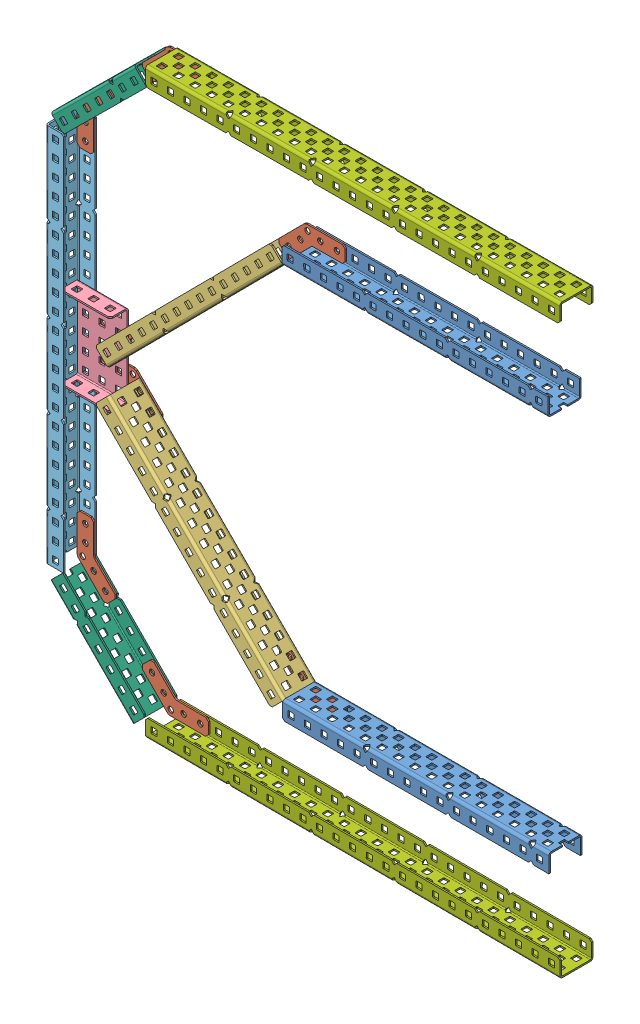
SolidWorks assembly Assem1, configuration Default. Lengths in mm.
Overall size (407.34 448.6 26.57).
18 component instances, 7 part files, 55 mates.
Components (placement in the parent):
- Channel 121-25 Aluminum-1: Channel 121-25 Aluminum [Default] at (-71.4802 130.2056 305.0856) size (203.98 13.87 25.4)
- 45 Degree Gusset Steel-1: 45 Degree Gusset Steel [Default] at (-111.3904 134.6957 291.8218) x (0.707107 0.707107 0) z (-0.707107 0.707107 0) size (29.13 1.17 50.81)
- Channel 121-15 Steel-1: Channel 121-15 Steel [Default] at (-213.9281 246.2136 305.0856) x (0.707107 -0.707107 0) z (0 0 1) size (190.5 13.87 25.4)
- 45 Degree Gusset Steel-4: 45 Degree Gusset Steel [Default] at (-228.1337 251.439 289.485) x (-0.707107 -0.707107 0) z (0.707107 -0.707107 0) size (29.13 1.17 50.81)
- Channel 151-15 Steel-1: Channel 151-15 Steel [Default] at (-405.6135 259.1091 290.6534) x (1 0 0) z (0 1 0) size (37.98 13.87 63.5)
- Channel 121-25 Aluminum-5: Channel 121-25 Aluminum [Default] at (-71.9919 420.4651 299.2845) x (0.999992 0.004 0) z (0 0 -1) size (203.98 13.87 25.4)
- 45 Degree Gusset Steel-11: 45 Degree Gusset Steel [Default] at (-111.8839 415.8408 290.6534) x (0.70993 -0.704273 0) z (-0.704273 -0.70993 0) size (29.13 1.17 50.81)
- Channel 121-15 Steel-5: Channel 121-15 Steel [Default] at (-213.9927 303.9315 299.2845) x (0.704273 0.70993 0) z (0 0 -1) size (190.5 13.87 25.4)
- 45 Degree Gusset Steel-12: 45 Degree Gusset Steel [Default] at (-228.1774 298.6493 288.3166) x (-0.70993 0.704273 0) z (0.704273 0.70993 0) size (29.13 1.17 50.81)
- 45 Degree Gusset Steel-13: 45 Degree Gusset Steel [Default] at (-262.514 115.5096 289.485) x (0.707107 0.707107 0) z (0.707107 -0.707107 0) size (29.13 1.17 50.81)
- 45 Degree Gusset Steel-14: 45 Degree Gusset Steel [Default] at (-262.514 434.5504 290.6534) x (0.707107 -0.707107 0) z (0.707107 0.707107 0) size (29.13 1.17 50.81)
- Channel 121-23 Aluminum-1: Channel 121-23 Aluminum [Default] at (-279.6787 130.0198 303.9172) x (0 1 0) z (0 0 1) size (291.03 13.87 25.4)
- Channel 121-7 Aluminum-1: Channel 121-7 Aluminum [Default] at (-257.2319 448.735 303.9172) x (0.70993 0.704273 0) z (0 0 1) size (89.86 13.87 25.4)
- Channel 121-7 Aluminum-4: Channel 121-7 Aluminum [Default] at (-231.9773 75.7112 303.9172) x (-0.704273 0.70993 0) z (0 0 1) size (89.86 13.87 25.4)
- 45 Degree Gusset Steel-15: 45 Degree Gusset Steel [Default] at (-191.6839 59.4664 289.485) x (0.004 0.999992 0) z (0.999992 -0.004 0) size (29.13 1.17 50.81)
- Channel 121-25 Al-1: Channel 121-25 Al [Default] at (86.8646 52.0022 303.9172) x (-0.999992 0.004 0) z (0 0 1) size (317.5 13.87 25.4)
- Channel 121-25 Al-3: Channel 121-25 Al [Default] at (86.8646 498.0578 298.1161) x (-0.999992 -0.004 0) z (0 0 -1) size (317.5 13.87 25.4)
- 45 Degree Gusset Steel-17: 45 Degree Gusset Steel [Default] at (-191.6839 490.5935 290.6534) x (0.004 -0.999992 0) z (0.999992 0.004 0) size (29.13 1.17 50.81)
Mates (geometry in assembly coordinates):
- Coincident2: coincident: plane of Channel 121-25 Aluminum-1 through (-97.9454 130.2056 314.885) normal (0 -1 0); plane of 45 Degree Gusset Steel-1 through (-72.52 130.2056 290.6534) normal (0 1 0)
- Coincident3: coincident: plane of Channel 121-25 Aluminum-1 through (-97.9454 130.2056 290.6534) normal (0 0 1); plane of 45 Degree Gusset Steel-1 through (-124.8608 139.1858 290.6534) normal (0 0 -1)
- Distance1: distance = 2.286 mm: cylinder of 45 Degree Gusset Steel-1 through (-78.87 123.8556 290.6534) axis (0 0 1) radius 2.0701; plane of Channel 121-25 Aluminum-1 through (-76.584 126.167 289.485) normal (-1 0 0)
- Coincident7: coincident: plane of 45 Degree Gusset Steel-1 through (-97.92 130.2056 290.6534) normal (0.707107 0.707107 0); plane of Channel 121-15 Steel-1 through (-232.6418 264.9274 314.885) normal (-0.707107 -0.707107 0)
- Coincident8: coincident: plane of 45 Degree Gusset Steel-1 through (-124.8608 139.1858 290.6534) normal (0 0 -1); plane of Channel 121-15 Steel-1 through (-232.6418 264.9274 290.6534) normal (0 0 1)
- Distance2: distance = 2.286 mm: plane of Channel 121-15 Steel-1 through (-103.6494 130.2235 289.485) normal (-0.707107 0.707107 0); cylinder of 45 Degree Gusset Steel-1 through (-106.9003 130.2056 290.6534) axis (0 0 1) radius 2.0701
- Coincident9: coincident: plane of Channel 121-15 Steel-1 through (-232.6418 264.9274 314.885) normal (-0.707107 -0.707107 0); plane of 45 Degree Gusset Steel-4 through (-232.6239 264.9094 288.3166) normal (0.707107 0.707107 0)
- Distance3: distance = 2.286 mm: cylinder of 45 Degree Gusset Steel-4 through (-223.6436 246.9489 288.3166) axis (0 0 1) radius 2.0701; plane of Channel 121-15 Steel-1 through (-220.3928 246.9669 289.485) normal (-0.707107 0.707107 0)
- Coincident11: coincident: plane of Channel 121-15 Steel-1 through (-232.6418 264.9274 289.485) normal (0 0 -1); plane of 45 Degree Gusset Steel-4 through (-214.6634 246.9489 289.485) normal (0 0 1)
- Coincident12: coincident: plane of 45 Degree Gusset Steel-4 through (-214.6634 246.9489 289.485) normal (0 0 1); plane of Channel 151-15 Steel-1 through (-432.0787 307.0086 289.485) normal (0 0 -1)
- Distance4: distance = 2.286 mm: plane of Channel 151-15 Steel-1 through (-250.2401 259.9932 292.025) normal (0 1 0); cylinder of 45 Degree Gusset Steel-4 through (-260.6541 262.2792 288.3166) axis (0 0 1) radius 2.0701
- Distance17: distance = 2.286 mm: cylinder of 45 Degree Gusset Steel-12 through (-260.6541 287.6792 289.485) axis (0 0 -1) radius 2.0701; plane of Channel 151-15 Steel-1 through (-250.2401 285.3932 292.025) normal (0 1 0)
- Coincident34: coincident: plane of Channel 151-15 Steel-1 through (-432.0787 307.0086 289.485) normal (0 0 -1); plane of 45 Degree Gusset Steel-12 through (-214.725 303.1933 289.485) normal (0 0 1)
- Coincident36: coincident: plane of Channel 121-15 Steel-5 through (-232.6315 285.143 289.485) normal (-0.70993 0.704273 0); plane of 45 Degree Gusset Steel-12 through (-232.6136 285.1611 289.485) normal (0.70993 -0.704273 0)
- Distance21: distance = 2.286 mm: plane of Channel 121-15 Steel-5 through (-220.4543 303.1524 314.885) normal (-0.704273 -0.70993 0); cylinder of 45 Degree Gusset Steel-12 through (-223.7052 303.1573 289.485) axis (0 0 -1) radius 2.0701
- Coincident37: coincident: plane of Channel 121-15 Steel-5 through (-232.6315 285.143 289.485) normal (0 0 -1); plane of 45 Degree Gusset Steel-12 through (-214.725 303.1933 289.485) normal (0 0 1)
- Distance22: distance = 2.286 mm: cylinder of 45 Degree Gusset Steel-11 through (-116.356 411.3327 291.8218) axis (0 0 -1) radius 2.0701; plane of Channel 121-15 Steel-5 through (-113.1232 411.3457 314.885) normal (-0.704273 -0.70993 0)
- Distance23: distance = 2.286 mm: cylinder of 45 Degree Gusset Steel-11 through (-116.356 411.3327 291.8218) axis (0 0 -1) radius 2.0701; plane of Channel 121-15 Steel-5 through (-116.3789 408.0638 314.885) normal (-0.70993 0.704273 0)
- Coincident40: coincident: plane of 45 Degree Gusset Steel-11 through (-125.3362 411.2968 290.6534) normal (0 0 -1); plane of Channel 121-15 Steel-5 through (-232.6315 285.143 290.6534) normal (0 0 1)
- Coincident41: coincident: plane of Channel 121-25 Aluminum-5 through (-98.4569 420.3592 290.6534) normal (0 0 1); plane of 45 Degree Gusset Steel-11 through (-125.3362 411.2968 290.6534) normal (0 0 -1)
- Distance24: distance = 2.286 mm: plane of Channel 121-25 Aluminum-5 through (-77.1118 424.4833 314.885) normal (-0.999992 -0.004 0); cylinder of 45 Degree Gusset Steel-11 through (-79.4071 426.8109 291.8218) axis (0 0 -1) radius 2.0701
- Distance25: distance = 2.286 mm: cylinder of 45 Degree Gusset Steel-11 through (-79.4071 426.8109 291.8218) axis (0 0 -1) radius 2.0701; plane of Channel 121-25 Aluminum-5 through (-81.7531 429.0875 314.885) normal (0.004 -0.999992 0)
- Coincident44: coincident: plane of Channel 151-15 Steel-1 through (-432.0787 307.0086 289.485) normal (0 0 -1); plane of Channel 121-23 Aluminum-1 through (-279.6787 103.5546 289.485) normal (0 0 1)
- Coincident46: coincident: plane of Channel 151-15 Steel-1 through (-271.0173 272.6932 292.025) normal (-1 0 0); plane of Channel 121-23 Aluminum-1 through (-271.0173 247.2932 288.3166) normal (-1 0 0)
- Coincident47: coincident: plane of Channel 151-15 Steel-1 through (-275.6401 272.6932 292.025) normal (0 1 0); plane of Channel 121-23 Aluminum-1 through (-275.6401 272.6932 288.3166) normal (0 1 0)
- Distance26: distance = 2.286 mm: cylinder of 45 Degree Gusset Steel-13 through (-273.3541 148.03 290.6534) axis (0 0 -1) radius 2.0701; plane of Channel 121-23 Aluminum-1 through (-275.6401 145.6932 288.3166) normal (1 0 0)
- Coincident48: coincident: plane of 45 Degree Gusset Steel-13 through (-258.0239 102.0392 289.485) normal (0 0 -1); plane of Channel 121-23 Aluminum-1 through (-279.6787 103.5546 289.485) normal (0 0 1)
- Parallel2: parallel: plane of 45 Degree Gusset Steel-13 through (-279.7041 124.8879 290.6534) normal (-1 0 0); plane of Channel 121-23 Aluminum-1 through (-279.6787 103.5546 313.7166) normal (1 0 0)
- Distance27: distance = 2.286 mm: plane of Channel 121-23 Aluminum-1 through (-275.6401 150.316 288.3166) normal (0 -1 0); cylinder of 45 Degree Gusset Steel-13 through (-273.3541 148.03 290.6534) axis (0 0 -1) radius 2.0701
- Distance29: distance = 2.286 mm: cylinder of 45 Degree Gusset Steel-12 through (-260.6541 287.6792 289.485) axis (0 0 -1) radius 2.0701; plane of Channel 151-15 Steel-1 through (-262.9401 285.3932 292.025) normal (1 0 0)
- Distance30: distance = 2.286 mm: cylinder of 45 Degree Gusset Steel-12 through (-247.9542 287.73 289.485) axis (0 0 -1) radius 2.0701; plane of Channel 151-15 Steel-1 through (-250.2401 290.016 292.025) normal (0 -1 0)
- Distance31: distance = 2.286 mm: cylinder of 45 Degree Gusset Steel-4 through (-260.6541 262.2792 288.3166) axis (0 0 1) radius 2.0701; plane of Channel 151-15 Steel-1 through (-262.9401 259.9932 292.025) normal (1 0 0)
- Distance32: distance = 2.286 mm: cylinder of 45 Degree Gusset Steel-4 through (-247.9541 262.2792 288.3166) axis (0 0 1) radius 2.0701; plane of Channel 151-15 Steel-1 through (-250.2401 259.9932 292.025) normal (0 1 0)
- Distance33: distance = 2.286 mm: cylinder of 45 Degree Gusset Steel-11 through (-107.4118 420.3488 291.8218) axis (0 0 -1) radius 2.0701; plane of Channel 121-15 Steel-5 through (-104.1789 420.3618 314.885) normal (-0.704273 -0.70993 0)
- Distance34: distance = 2.286 mm: plane of Channel 121-25 Aluminum-5 through (-89.8117 424.4325 314.885) normal (-0.999992 -0.004 0); cylinder of 45 Degree Gusset Steel-11 through (-92.107 426.7601 291.8218) axis (0 0 -1) radius 2.0701
- Coincident53: coincident: plane of Channel 151-15 Steel-1 through (-271.0173 247.2932 292.025) normal (-1 0 0); plane of Channel 121-23 Aluminum-1 through (-271.0173 247.2932 288.3166) normal (-1 0 0)
- Coincident54: coincident: plane of 45 Degree Gusset Steel-14 through (-258.0239 448.0207 289.485) normal (0 0 -1); plane of Channel 121-23 Aluminum-1 through (-279.6787 103.5546 289.485) normal (0 0 1)
- Distance36: distance = 2.286 mm: plane of Channel 121-23 Aluminum-1 through (-275.6401 399.6932 288.3166) normal (1 0 0); cylinder of 45 Degree Gusset Steel-14 through (-273.3541 402.03 289.485) axis (0 0 1) radius 2.0701
- Distance37: distance = 2.286 mm: cylinder of 45 Degree Gusset Steel-14 through (-273.3541 402.03 289.485) axis (0 0 1) radius 2.0701; plane of Channel 121-23 Aluminum-1 through (-275.6401 404.316 288.3166) normal (0 -1 0)
- Distance40: distance = 2.286 mm: cylinder of 45 Degree Gusset Steel-14 through (-273.3541 414.73 289.485) axis (0 0 1) radius 2.0701; plane of Channel 121-23 Aluminum-1 through (-275.6401 412.3932 288.3166) normal (1 0 0)
- Coincident55: coincident: plane of 45 Degree Gusset Steel-14 through (-258.0239 448.0207 289.485) normal (0 0 -1); plane of Channel 121-7 Aluminum-1 through (-276.0203 430.0962 289.485) normal (0 0 1)
- Distance42: distance = 2.286 mm: plane of Channel 121-7 Aluminum-1 through (-261.2928 439.0176 288.3166) normal (0.704273 -0.70993 0); cylinder of 45 Degree Gusset Steel-14 through (-258.0239 439.0405 289.485) axis (0 0 1) radius 2.0701
- Distance43: distance = 2.286 mm: plane of Channel 121-7 Aluminum-1 through (-258.0109 442.2733 288.3166) normal (-0.70993 -0.704273 0); cylinder of 45 Degree Gusset Steel-14 through (-258.0239 439.0405 289.485) axis (0 0 1) radius 2.0701
- Distance45: distance = 2.286 mm: plane of Channel 121-7 Aluminum-1 through (-267.0532 426.7915 288.3166) normal (-0.704273 0.70993 0); cylinder of 45 Degree Gusset Steel-14 through (-267.0041 430.0602 289.485) axis (0 0 1) radius 2.0701
- Coincident58: coincident: plane of 45 Degree Gusset Steel-13 through (-258.0239 102.0392 289.485) normal (0 0 -1); plane of Channel 121-7 Aluminum-4 through (-213.3385 56.9228 289.485) normal (0 0 1)
- Distance55: distance = 2.286 mm: plane of Channel 121-7 Aluminum-4 through (-266.9813 116.7308 288.3166) normal (0.70993 0.704273 0); cylinder of 45 Degree Gusset Steel-13 through (-267.0041 119.9997 290.6534) axis (0 0 -1) radius 2.0701
- Distance56: distance = 2.286 mm: plane of Channel 121-7 Aluminum-4 through (-270.237 120.0126 288.3166) normal (0.704273 -0.70993 0); cylinder of 45 Degree Gusset Steel-13 through (-267.0041 119.9997 290.6534) axis (0 0 -1) radius 2.0701
- Distance57: distance = 2.286 mm: cylinder of 45 Degree Gusset Steel-13 through (-258.0239 111.0195 290.6534) axis (0 0 -1) radius 2.0701; plane of Channel 121-7 Aluminum-4 through (-254.7552 110.9704 288.3166) normal (-0.70993 -0.704273 0)
- Coincident61: coincident: plane of Channel 121-7 Aluminum-4 through (-213.3385 56.9228 289.485) normal (0 0 1); plane of 45 Degree Gusset Steel-15 through (-179.0094 53.0657 289.485) normal (0 0 -1)
- Distance58: distance = 2.286 mm: cylinder of 45 Degree Gusset Steel-15 through (-222.2828 74.9192 290.6534) axis (0 0 -1) radius 2.0701; plane of Channel 121-7 Aluminum-4 through (-225.5157 74.9321 288.3166) normal (0.704273 -0.70993 0)
- Distance60: distance = 2.286 mm: plane of Channel 121-7 Aluminum-4 through (-222.26 71.6503 288.3166) normal (0.70993 0.704273 0); cylinder of 45 Degree Gusset Steel-15 through (-222.2828 74.9192 290.6534) axis (0 0 -1) radius 2.0701
- Distance61: distance = 2.286 mm: cylinder of 45 Degree Gusset Steel-15 through (-213.3385 65.9031 290.6534) axis (0 0 -1) radius 2.0701; plane of Channel 121-7 Aluminum-4 through (-213.3157 62.6341 288.3166) normal (0.70993 0.704273 0)
- Coincident63: coincident: plane of 45 Degree Gusset Steel-15 through (-204.4092 53.1673 290.6534) normal (-0.004 -0.999992 0); plane of Channel 121-25 Al-1 through (113.3296 51.8963 313.7166) normal (0.004 0.999992 0)
- Coincident64: coincident: plane of 45 Degree Gusset Steel-15 through (-179.0094 53.0657 289.485) normal (0 0 -1); plane of Channel 121-25 Al-1 through (113.3296 51.8963 289.485) normal (0 0 1)
- Tangent25: tangent: cylinder of 45 Degree Gusset Steel-15 through (-198.0338 59.4918 290.6534) axis (0 0 -1) radius 2.0701; plane of Channel 121-25 Al-1 through (-200.1131 57.1887 288.3166) normal (0.999992 -0.004 0)
